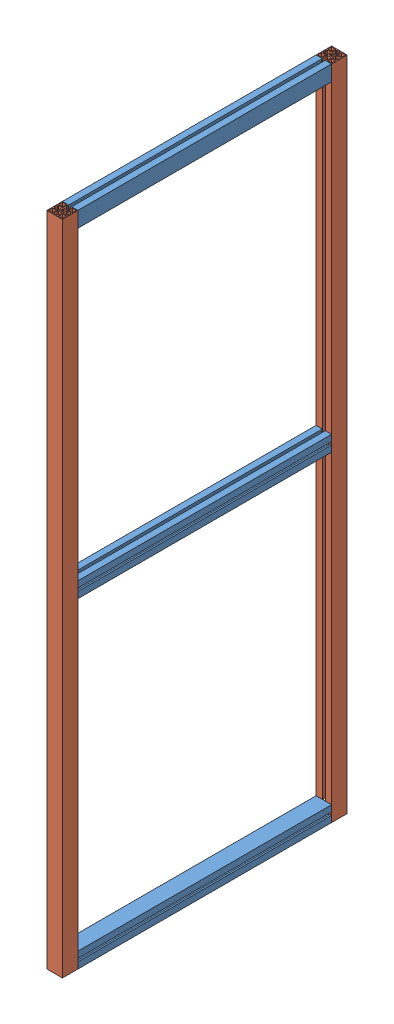
SolidWorks assembly short_side_frame, configuration Default. Lengths in mm.
Overall size (45 1907.79 826.6).
9 component instances, 5 part files, 12 mates.
Components (placement in the parent):
- 20.1028 45X45 G_29in-1: 20.1028 45X45 G_29in [Default] at (347.66 229.1726 203.0511) size (45 45 736.6)
- 20.1028 45X45 G_29in-2: 20.1028 45X45 G_29in [inner] at (347.6601 1160.5112 939.6511) x (1 0 0) z (0 0 -1) size (45 45 736.6)
- 20.1028 45X45 G_7172in-1: 20.1028 45X45 G_7172in [Default] at (347.661 206.6719 180.5518) x (-1 0 0) z (0 1 0) size (45 45 1907.79)
- 21.0818 POWER-LOCK SF-1: 21.0818 POWER-LOCK SF [Default] at (347.6605 236.3741 194.9917) x (0 1 0) z (1 0 0) size (30.48 29.4 18.46)
  - 21.1018 POWER-LOCK BODY-1: 21.1018 POWER-LOCK BODY [Default] at origin size (28.09 14.81 12.77)
  - 21.1492 POWER-LOCK SF TORX SCREW-1: 21.1492 POWER-LOCK SF TORX SCREW [Default] at (-7.2022 -2 0) x (-0.864303 0 -0.502971) z (-0.502971 0 0.864303) size (13.5 29.4 13.5)
  - 21.1301 M8X16 SET SCREW FLAT DIN 913-1: 21.1301 M8X16 SET SCREW FLAT DIN 913 [Default] at (0.7679 -2.7963 0) x (0.411587 0.911371 0) z (0.117457 -0.053045 0.99166) size (16 8 8)
- 20.1028 45X45 G_29in-3: 20.1028 45X45 G_29in [Default] at (347.6611 2091.9652 203.0511) x (-1 0 0) z (0 0 1) size (45 45 736.6)
- 20.1028 45X45 G_7172in-2: 20.1028 45X45 G_7172in [Default] at (347.66 206.6719 962.1504) x (1 0 0) z (0 1 0) size (45 45 1907.79)
Mates (geometry in assembly coordinates):
- Coincident2: coincident anti-aligned: plane of 20.1028 45X45 G_29in-1 through (347.66 229.1726 203.0511) normal (0 0 1); plane of 20.1028 45X45 G_29in-2 through (347.6601 1160.5112 203.0511) normal (0 0 -1)
- Coincident10: coincident anti-aligned: plane of 20.1028 45X45 G_29in-1 through (347.66 229.1726 203.0511) normal (0 0 -1); plane of 20.1028 45X45 G_7172in-1 through (347.6611 2114.4659 203.0511) normal (0 0 1)
- Coincident11: coincident aligned: line of 20.1028 45X45 G_29in-1 through (325.1605 206.6719 203.0511) axis (1 0 0); line of 20.1028 45X45 G_7172in-1 through (325.1605 206.6719 203.0511) axis (1 0 0)
- Coincident12: coincident anti-aligned: line of 20.1028 45X45 G_29in-1 through (370.1605 206.6719 203.0511) axis (0 1 0); line of 20.1028 45X45 G_7172in-1 through (370.1606 2114.4659 203.0511) axis (0 -1 0)
- Parallel11: parallel aligned: plane of 20.1028 45X45 G_29in-1 through (347.66 206.6719 939.6511) normal (0 -1 0); plane of 21.0818 POWER-LOCK SF-1/21.1018 POWER-LOCK BODY-1 through (347.6605 222.3279 202.9917) normal (0 -1 0)
- Concentric4: concentric aligned: circle of 20.1028 45X45 G_29in-1; circle of 21.0818 POWER-LOCK SF-1/21.1492 POWER-LOCK SF TORX SCREW-1
- Coincident25: coincident anti-aligned: plane of 20.1028 45X45 G_7172in-1 through (347.6611 2114.4659 203.0511) normal (0 0 1); plane of 20.1028 45X45 G_29in-3 through (347.6611 2091.9652 203.0511) normal (0 0 -1)
- Coincident28: coincident anti-aligned: line of 20.1028 45X45 G_7172in-1 through (370.1606 2114.4659 203.0511) axis (0 -1 0); line of 20.1028 45X45 G_29in-3 through (370.1606 2069.4659 203.0511) axis (0 1 0)
- Coincident29: coincident anti-aligned: line of 20.1028 45X45 G_7172in-1 through (351.9106 2114.4659 203.0511) axis (1 0 0); line of 20.1028 45X45 G_29in-3 through (370.1606 2114.4659 203.0511) axis (-1 0 0)
- Distance5: distance = 916.94 mm anti-aligned: plane of 20.1028 45X45 G_29in-2 through (347.6601 1153.3119 203.0511) normal (0 -1 0); plane of 20.1028 45X45 G_29in-1 through (347.66 236.3719 939.6511) normal (0 1 0)
- Coincident31: coincident aligned: line of 20.1028 45X45 G_29in-3 through (325.1606 2114.4659 939.6511) axis (0 -1 0); line of 20.1028 45X45 G_7172in-2 through (325.1606 2114.4659 939.6511) axis (0 -1 0)
- Coincident32: coincident aligned: line of 20.1028 45X45 G_29in-3 through (370.1606 2114.4659 939.6511) axis (-1 0 0); line of 20.1028 45X45 G_7172in-2 through (343.4105 2114.4659 939.6511) axis (-1 0 0)
